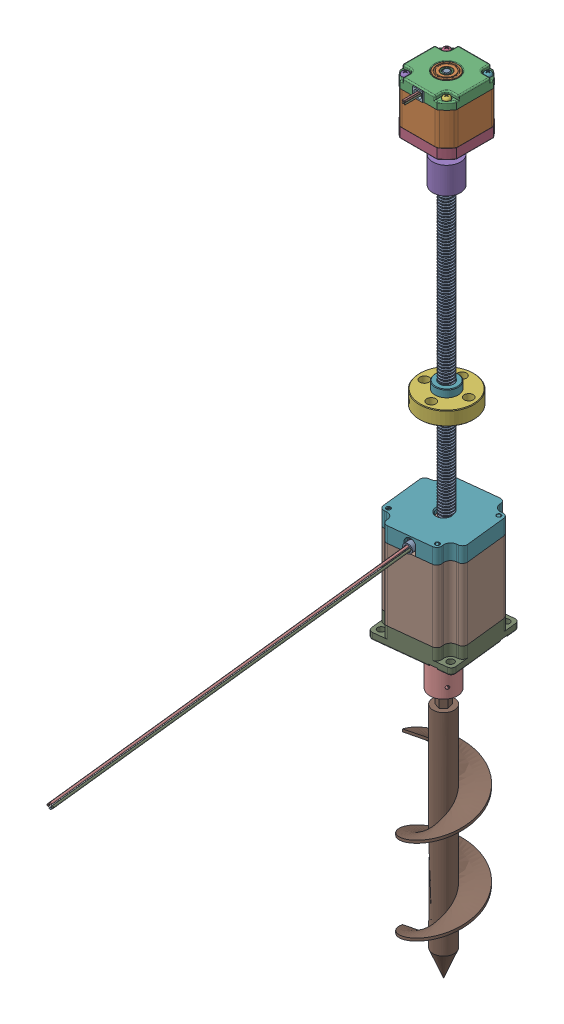
SolidWorks assembly Rhino Actuation SubassemblyV2, configuration Default. Lengths in mm.
Overall size (96.63 587.76 366.09).
7 component instances, 7 part files, 25 mates.
Components (placement in the parent):
- 7549K71_Lead Screw-1: 7549K71_Lead Screw [7549K71] at (0.0601 11.5542 -2.1836) x (0.585983 0 -0.810323) z (0 1 0) size (10.51 10 260.86)
- 6627T67_Stepper Motor-1: 6627T67_Stepper Motor [6627T67] at (0.0601 165.5542 -2.1836) x (1 0 0) z (0 -1 0) size (42.42 53.3 64.13)
- AdapterCoupling-1: AdapterCoupling [Default] at (0.0601 131.5542 -2.1836) x (-0.847583 0 0.530662) z (-0.530662 0 -0.847583) size (20.64 20 20.64)
- 7549K16_Precision Acme Flange Nut-1: 7549K16_Precision Acme Flange Nut [7549K16] at (0.0601 -10.9461 -2.1836) x (0 1 0) z (0.182034 0 0.983292) size (16.19 40.64 40.64)
- 6627T54_Stepper Motor-1: 6627T54_Stepper Motor [6627T54] at (0 -108.7337 0) x (-0.993944 0 0.109885) z (0 -1 0) size (57.2 362 99.46)
- MotorAugerCoupling-1: MotorAugerCoupling [Default] at (0 -163.8767 0) x (0 -1 0) z (-0.551698 0 0.834044) size (30 20.66 20.64)
- Auger3-1: Auger3 [Default] at (0 -204.2767 0) x (0.970942 0 -0.239313) z (0.239313 0 0.970942) size (51.2 203.2 51.32)
Mates (geometry in assembly coordinates):
- Screw3: screw = 2 mm anti-aligned: circle of 7549K71_Lead Screw-1; cylinder of 7549K16_Precision Acme Flange Nut-1 through (0.0601 4.9289 -2.1836) axis (0 -1 0) radius 8.636
- Concentric6: concentric aligned: cylinder of 6627T67_Stepper Motor-1 through (0.0601 141.5542 -2.1836) axis (0 -1 0) radius 2.5; cylinder of AdapterCoupling-1 through (0.0601 131.5542 -2.1836) axis (0 -1 0) radius 2.5
- Coincident3: coincident aligned: plane of 6627T67_Stepper Motor-1 through (0.0601 141.5542 0.3164) normal (0 -1 0); plane of AdapterCoupling-1 through (4.298 141.5542 -4.8369) normal (0 -1 0)
- Concentric7: concentric aligned: cylinder of 7549K71_Lead Screw-1 through (0.0601 -118.4458 -2.1836) axis (0 -1 0) radius 5; cylinder of AdapterCoupling-1 through (0.0601 131.5542 -2.1836) axis (0 -1 0) radius 5
- Coincident4: coincident anti-aligned: plane of 7549K71_Lead Screw-1 through (0.0601 141.5542 -2.1836) normal (0 1 0); plane of AdapterCoupling-1 through (4.298 141.5542 -4.8369) normal (0 -1 0)
- Concentric8: concentric anti-aligned: circle of 6627T67_Stepper Motor-1; cylinder of MotorPlate-1 through (15.5 201.2883 -15.5) axis (0 1 0) radius 1.6
- Concentric11: concentric anti-aligned: circle of 6627T67_Stepper Motor-1; cylinder of MotorPlate-1 through (15.5 201.2883 15.5) axis (0 1 0) radius 1.6
- Coincident5: coincident anti-aligned: plane of 6627T67_Stepper Motor-1 through (0.0601 165.5542 -2.1836) normal (0 -1 0); plane of MotorPlate-1 through (0 204.4633 0) normal (0 1 0)
- LimitDistance1: limit distance = 215.7125 mm anti-aligned: plane of AdapterCoupling-1 through (8.8061 131.5542 -7.6594) normal (0 -1 0); plane of 7549K88_Precision Nut with M10 x 2mm External Thread for Lead Screw-1 through (-5 6.35 0) normal (0 1 0)
- Concentric14: concentric anti-aligned: cylinder of 7549K88_Precision Nut with M10 x 2mm External Thread for Lead Screw-1 through (0 -10.1018 -10.6438) axis (0 1 0) radius 3; cylinder of 90156A611_Flat-Head Quick-Release Pins-1 through (0 -18.65 -10.6438) axis (0 -1 0) radius 3
- Coincident11: coincident anti-aligned: plane of 7549K88_Precision Nut with M10 x 2mm External Thread for Lead Screw-1 through (-5 6.35 0) normal (0 1 0); plane of 90156A611_Flat-Head Quick-Release Pins-1 through (-2.6967 6.35 -11.9581) normal (0 -1 0)
- Coincident12: coincident anti-aligned: plane of DrillingPlatformRhino-1 through (0 0 0) normal (0 1 0); plane of Simple Bracket-1 through (-21.025 0 4.5) normal (0 -1 0)
- Distance1: distance = 20 mm aligned: plane of Nut Bracket-1 through (0 -7.9375 -10.6438) normal (0 -1 0); plane of 7549K71_Lead Screw-1 through (0.0601 -118.4458 -2.1836) normal (0 -1 0)
- Concentric16: concentric anti-aligned: cylinder of DrillingPlatformRhino-1 through (0 -1.5875 0) axis (0 1 0) radius 7.5406; cylinder of 7549K16_Precision Acme Flange Nut-1 through (0.0601 4.9289 -2.1836) axis (0 -1 0) radius 8.636
- Coincident14: coincident anti-aligned: plane of DrillingPlatformRhino-1 through (0 -1.5875 0) normal (0 -1 0); plane of 7549K16_Precision Acme Flange Nut-1 through (0.0601 -0.5321 -2.1836) normal (0 1 0)
- Concentric17: concentric anti-aligned: cylinder of DrillingPlatformRhino-1 through (14.2875 -155.5775 0) axis (0 1 0) radius 3.175; cylinder of 7549K16_Precision Acme Flange Nut-1 through (2.6609 9.0229 11.8652) axis (0 -1 0) radius 3.3782
- Concentric18: concentric anti-aligned: circle of 7549K71_Lead Screw-1; cylinder of BottomMotorPlate-1 through (0 -73.1867 0) axis (0 -1 0) radius 5
- Coincident15: coincident aligned: plane of 7549K71_Lead Screw-1 through (0.0601 -118.4458 -2.1836) normal (0 -1 0); plane of BottomMotorPlate-1 through (0 -79.5367 0) normal (0 -1 0)
- Concentric19: concentric aligned: cylinder of BottomMotorPlate-1 through (-26.0173 -73.1867 -20.8373) axis (0 -1 0) radius 2.75; cylinder of 6627T54_Stepper Motor-1 through (-26.0504 -79.5367 -20.8638) axis (0 -1 0) radius 2.55
- Concentric22: concentric aligned: cylinder of BottomMotorPlate-1 through (-20.8373 -73.1867 26.0173) axis (0 -1 0) radius 2.75; cylinder of 6627T54_Stepper Motor-1 through (-20.8638 -144.6287 26.0504) axis (0 -1 0) radius 2.55
- Coincident16: coincident anti-aligned: plane of BottomMotorPlate-1 through (0 -79.5367 0) normal (0 -1 0); plane of 6627T54_Stepper Motor-1 through (0 -79.5367 0) normal (0 1 0)
- Concentric23: concentric anti-aligned: cylinder of 6627T54_Stepper Motor-1 through (0 -178.8767 0) axis (0 -1 0) radius 3.1725; cylinder of MotorAugerCoupling-1 through (0 516.4513 0) axis (0 1 0) radius 2.925
- Coincident17: coincident anti-aligned: plane of 6627T54_Stepper Motor-1 through (-0.3486 -178.8767 -3.1533) normal (0 -1 0); plane of MotorAugerCoupling-1 through (2.4396 -178.8767 1.6137) normal (0 1 0)
- Concentric24: concentric anti-aligned: cylinder of MotorAugerCoupling-1 through (0 516.4513 0) axis (0 1 0) radius 2.925; cylinder of Auger3-1 through (0 -382.0767 0) axis (0 -1 0) radius 7.9375
- Coincident18: coincident anti-aligned: plane of 6627T54_Stepper Motor-1 through (-0.3486 -178.8767 -3.1533) normal (0 -1 0); plane of Auger3-1 through (0 -178.8767 0) normal (0 1 0)
